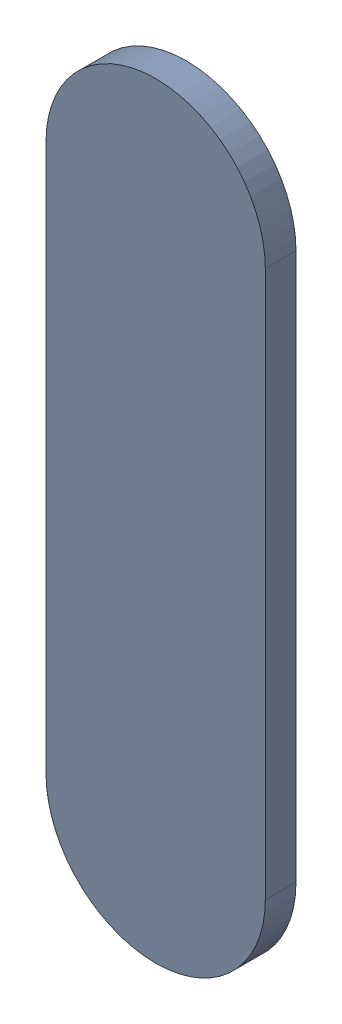
SolidWorks assembly Track (19.304mm,48.07mm)(19.304mm,48.704mm) on Bottom Layer, configuration Predeterminado. Lengths in mm.
Overall size (0.25 0.89 0.04).
2 component instances, 1 part files, 0 mates.
Components (placement in the parent):
- Track (19.304mm,48.07mm)(19.304mm,48.704mm) on Bottom Layer-1-1: Track (19.304mm,48.07mm)(19.304mm,48.704mm) on Bottom Layer-1 [Predeterminado] at (-68.317 -44.187 -0.4013) size (0.25 0.89 0.04)
  - Track (19.304mm,48.07mm)(19.304mm,48.704mm) on Bottom Layer-Part-1-1: Track (19.304mm,48.07mm)(19.304mm,48.704mm) on Bottom Layer-Part-1 [Predeterminado] at origin size (0.25 0.89 0.04)
